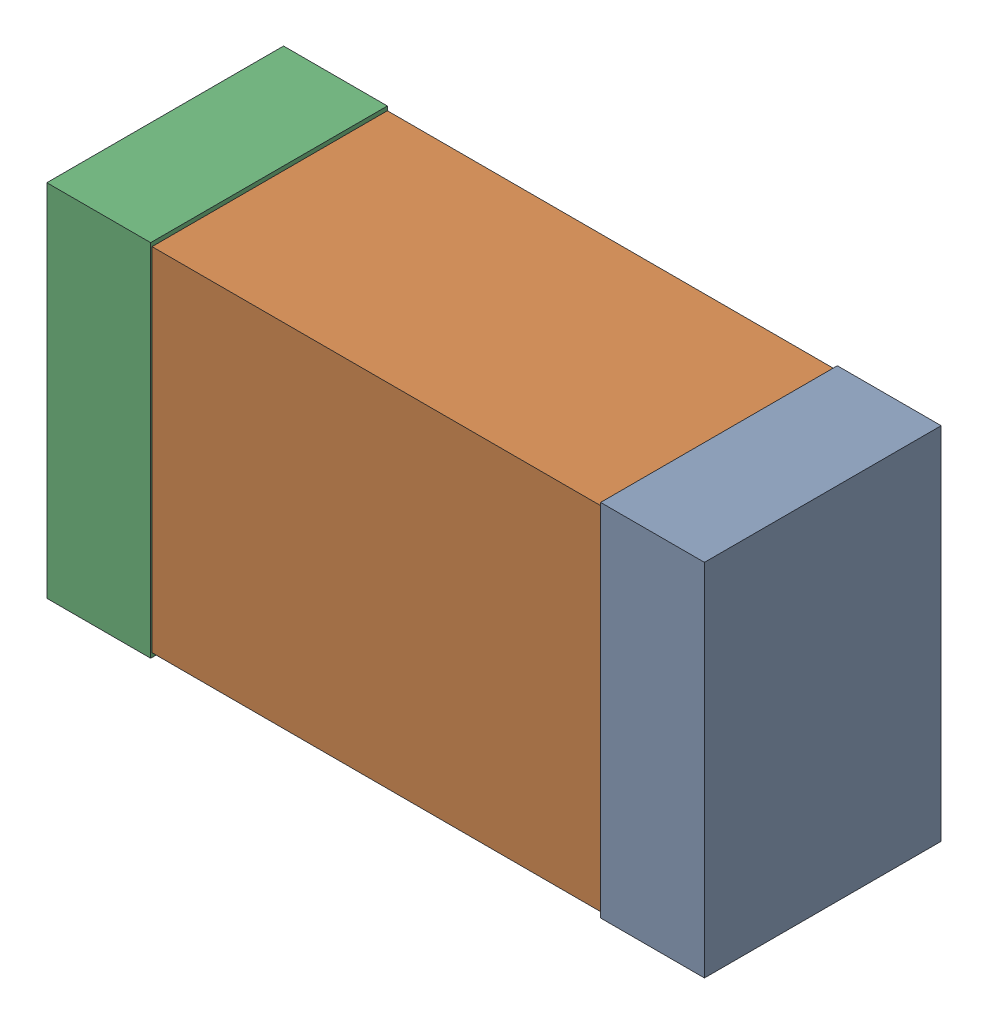
SolidWorks assembly C4, configuration Default. Lengths in mm.
Overall size (2.38 1.3 0.85).
6 component instances, 2 part files, 0 mates.
Components (placement in the parent):
- 384311232-1: 384311232 [Default] at (152.4094 86.1822 0) size (0.38 1.3 0.85)
  - Extruded_8-1: Extruded_8 [Default] at origin size (0.38 1.3 0.85)
- 384311360-1: 384311360 [Default] at (151.4094 86.1822 0) size (2.2 1.27 0.85)
  - Extruded_9-1: Extruded_9 [Default] at origin size (2.2 1.27 0.85)
- 384311232-2: 384311232 [Default] at (150.4094 86.1822 0) size (0.38 1.3 0.85)
  - Extruded_8-1: Extruded_8 [Default] at origin size (0.38 1.3 0.85)
